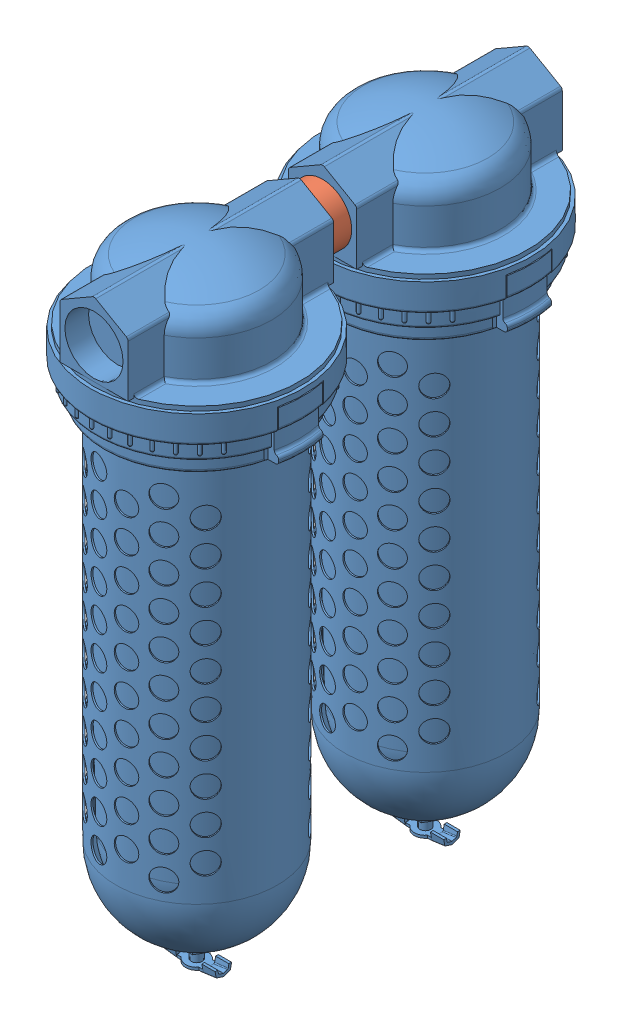
SolidWorks assembly ReadingTech_3P-150-P08-DCP, configuration Default. Lengths in mm.
Overall size (121.86 360.29 252.73).
3 component instances, 2 part files, 3 mates.
Components (placement in the parent):
- ReadingTech_3P-150-P08-P-1: ReadingTech_3P-150-P08-P [Default] at (-28.4571 -214.7657 2.6805) size (121.86 360.29 121.67)
- ReadingTech_3P-150-P08-P-2: ReadingTech_3P-150-P08-P [Default] at (-28.4571 -214.7657 -128.3835) size (121.86 360.29 121.67)
- ReadingTech- 90,150cfm_connector_1in-1: ReadingTech- 90,150cfm_connector_1in [Default] at (-28.4571 174.2353 -56.2475) x (1 0 0) z (0 1 0) size (33.4 13.21 33.4)
Mates (geometry in assembly coordinates):
- Coincident1: coincident anti-aligned: circle of ReadingTech_3P-150-P08-P-2; circle of ReadingTech- 90,150cfm_connector_1in-1
- Coincident2: coincident aligned: circle of ReadingTech_3P-150-P08-P-1; circle of ReadingTech- 90,150cfm_connector_1in-1
- Coincident3: coincident aligned: plane of ReadingTech_3P-150-P08-P-1 through (-8.8991 186.9353 61.6085) normal (1 0 0); plane of ReadingTech_3P-150-P08-P-2 through (-8.8991 186.9353 -69.4555) normal (1 0 0)
